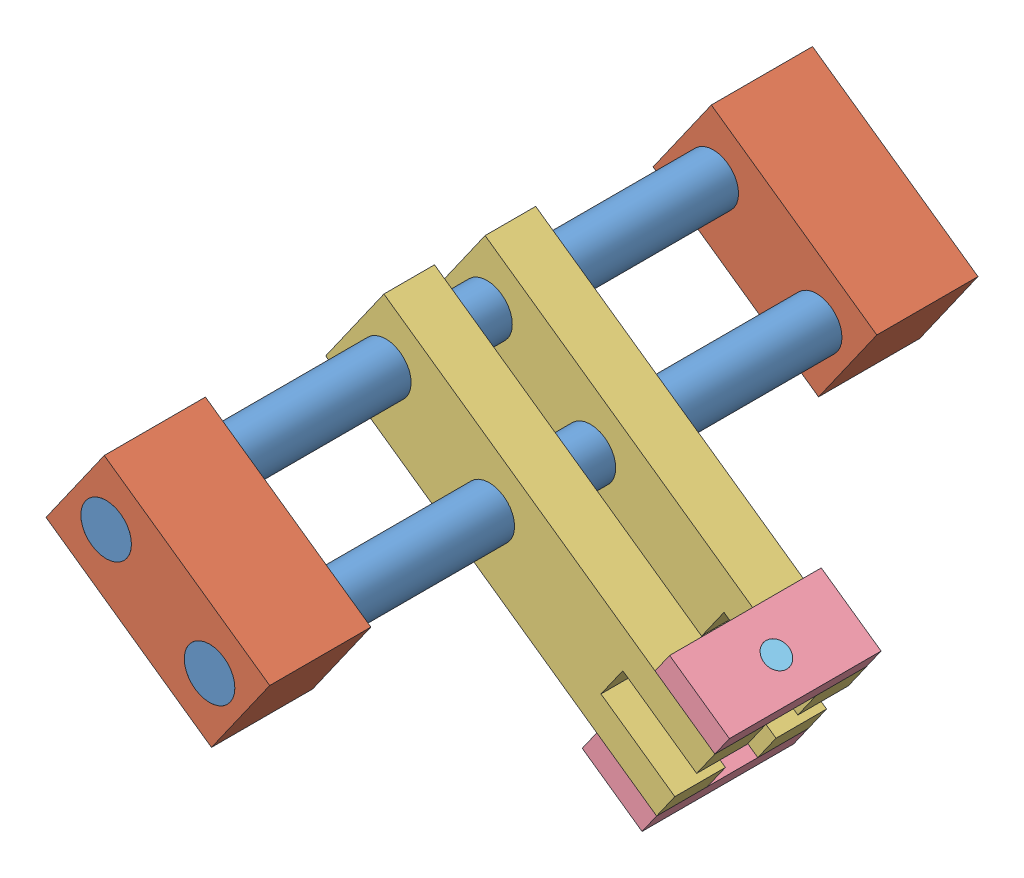
SolidWorks assembly Initial Assembly - Leadscrew portion, configuration Default. Lengths in mm.
Overall size (202.71 168.89 355.6).
9 component instances, 5 part files, 22 mates.
Components (placement in the parent):
- leadscrew-1: leadscrew [Default] at (108.2337 189.9319 148.9003) size (25.4 25.4 355.6)
- leadscrew-2: leadscrew [Default] at (56.309 226.4841 148.9003) size (25.4 25.4 355.6)
- Leadscrew Holder-1: Leadscrew Holder [Default] at (138.4321 199.7361 453.7003) x (0 0 1) z (-0.575626 -0.817713 0) size (50.8 101.6 50.8)
- Leadscrew Holder-2: Leadscrew Holder [Default] at (138.4321 199.7361 148.9003) x (0 0 1) z (-0.575626 -0.817713 0) size (50.8 101.6 50.8)
- Wheel holder-1: Wheel holder [Default] at (192.2699 99.7126 338.6926) x (0.575626 0.817713 0) z (0 0 1) size (50.8 203.2 25.4)
- Wheel holder-2: Wheel holder [Default] at (192.2699 99.7126 287.8926) x (0.575626 0.817713 0) z (0 0 1) size (50.8 203.2 25.4)
- Side plate wheel-1: Side plate wheel [Default] at (228.8222 151.6374 287.95) x (0 0 1) z (-0.575626 -0.817713 0) size (76.14 36.73 12.7)
- Side plate wheel-2: Side plate wheel [Default] at (184.9594 89.3277 364.0926) x (0 0 -1) z (0.575626 0.817713 0) size (76.14 36.73 12.7)
- Wheel Axle-2: Wheel Axle [Default] at (214.366 161.8137 326.05) x (0.287572 -0.202435 0.936121) z (-0.575626 -0.817713 0) size (12.7 12.7 76.2)
Mates (geometry in assembly coordinates):
- Concentric1: concentric anti-aligned: cylinder of leadscrew-2 through (56.309 226.4841 504.5003) axis (0 0 -1) radius 12.7; cylinder of Leadscrew Holder-1 through (56.309 226.4841 453.7003) axis (0 0 1) radius 12.7
- Concentric2: concentric anti-aligned: cylinder of leadscrew-1 through (108.2337 189.9319 504.5003) axis (0 0 -1) radius 12.7; cylinder of Leadscrew Holder-1 through (108.2337 189.9319 453.7003) axis (0 0 1) radius 12.7
- Coincident1: coincident anti-aligned: cylinder of leadscrew-2 through (56.309 226.4841 504.5003) axis (0 0 -1) radius 12.7; circle of Leadscrew Holder-2
- Concentric3: concentric anti-aligned: cylinder of leadscrew-1 through (108.2337 189.9319 504.5003) axis (0 0 -1) radius 12.7; cylinder of Leadscrew Holder-2 through (108.2337 189.9319 148.9003) axis (0 0 1) radius 12.7
- Parallel1: parallel aligned: plane of leadscrew-2 through (56.309 226.4841 504.5003) normal (0 0 1); plane of Leadscrew Holder-1 through (109.1903 158.1963 504.5003) normal (0 0 1)
- Coincident2: coincident aligned: circle of leadscrew-2; circle of Leadscrew Holder-1
- Coincident3: coincident aligned: circle of leadscrew-1; circle of Leadscrew Holder-1
- Coincident4: coincident aligned: circle of leadscrew-2; circle of Leadscrew Holder-2
- Coincident6: coincident aligned: circle of leadscrew-1; circle of Leadscrew Holder-2
- Concentric4: concentric anti-aligned: cylinder of leadscrew-2 through (56.309 226.4841 504.5003) axis (0 0 -1) radius 12.7; cylinder of Wheel holder-1 through (56.309 226.4841 338.6926) axis (0 0 1) radius 12.7
- Concentric5: concentric anti-aligned: cylinder of leadscrew-1 through (108.2337 189.9319 504.5003) axis (0 0 -1) radius 12.7; cylinder of Wheel holder-1 through (108.2337 189.9319 338.6926) axis (0 0 1) radius 12.7
- Concentric6: concentric anti-aligned: cylinder of leadscrew-2 through (56.309 226.4841 504.5003) axis (0 0 -1) radius 12.7; cylinder of Wheel holder-2 through (56.309 226.4841 287.8926) axis (0 0 1) radius 12.7
- Concentric7: concentric anti-aligned: cylinder of leadscrew-1 through (108.2337 189.9319 504.5003) axis (0 0 -1) radius 12.7; cylinder of Wheel holder-2 through (108.2337 189.9319 287.8926) axis (0 0 1) radius 12.7
- Distance1: distance = 25.4 mm: line of Wheel holder-1 through (55.3525 258.2197 338.6926) axis (-0.575626 -0.817713 0); line of Wheel holder-2 through (55.3525 258.2197 313.2926) axis (-0.575626 -0.817713 0)
- Coincident10: coincident anti-aligned: plane of Wheel holder-1 through (192.2699 99.7126 364.0926) normal (-0.575626 -0.817713 0); plane of Side plate wheel-2 through (192.2699 99.7126 364.0926) normal (0.575626 0.817713 0)
- Coincident11: coincident aligned: line of Wheel holder-1 through (26.1106 216.6799 364.0926) axis (0.817713 -0.575626 0); line of Side plate wheel-2 through (162.2363 120.8547 364.0926) axis (0.817713 -0.575626 0)
- Coincident12: coincident aligned: line of Wheel holder-1 through (192.2699 99.7126 364.0926) axis (0 0 -1); line of Side plate wheel-2 through (192.2699 99.7126 364.0926) axis (0 0 -1)
- Coincident13: coincident anti-aligned: plane of Wheel holder-1 through (221.5117 141.2524 364.0926) normal (0.575626 0.817713 0); plane of Side plate wheel-1 through (221.5117 141.2524 287.95) normal (-0.575626 -0.817713 0)
- Coincident14: coincident aligned: line of Wheel holder-1 through (221.5117 141.2524 364.0926) axis (-0.817713 0.575626 0); line of Side plate wheel-1 through (221.5117 141.2524 364.0926) axis (-0.817713 0.575626 0)
- Coincident15: coincident anti-aligned: line of Wheel holder-1 through (221.5117 141.2524 364.0926) axis (0 0 -1); line of Side plate wheel-1 through (221.5117 141.2524 287.95) axis (0 0 1)
- Concentric9: concentric anti-aligned: axis of Side plate wheel-1 through (214.366 161.8137 326.05) axis (-0.575626 -0.817713 0); cylinder of Wheel Axle-2 through (170.5033 99.504 326.05) axis (0.575626 0.817713 0) radius 6.35
- Coincident16: coincident aligned: circle of Side plate wheel-1; circle of Wheel Axle-2
